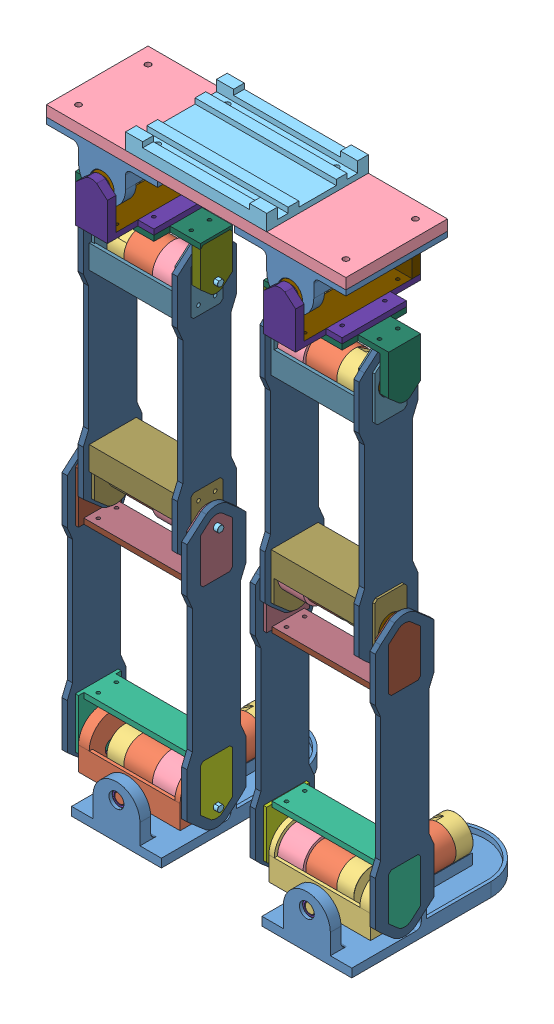
SolidWorks assembly Biped, configuration Default. Lengths in mm.
Overall size (293 593.93 211.17).
118 component instances, 23 part files, 10 mates.
Components (placement in the parent):
- Leg Left-1: Leg Left [Default] at (-89 -541.9264 -37) size (121 569.75 211.17) (flexible)
  - Foot-1: Foot [Default] at origin size (89.58 49 186.67)
  - Motor-1: Motor [Default] at (14.2667 22.6871 -73.752) x (-1 0 0) z (0 0 1) size (45.64 45.64 90) (flexible)
    - Motor Proper-1: Motor Proper [Default] at (14.2667 22.6871 35.252) x (0.971375 -0.237549 0) z (0 0 1) size (33 33 29)
    - Motor Encoder-1: Motor Encoder [Default] at (14.2667 22.6871 20.752) x (0.839139 0.543917 0) z (0 0 1) size (33 33 16)
    - Motor Gearbox-1: Motor Gearbox [Default] at (14.2667 22.6871 49.752) size (38 38 30)
    - Motor Shaft-1: Motor Shaft [Default] at (14.2667 15.6871 60.752) size (6 6 34)
  - Motor-2: Motor [Default] at (-31.252 -0.6871 50.2667) x (0 0 -1) z (1 0 0) size (45.64 45.64 90) (flexible)
    - Motor Proper-1: Motor Proper [Default] at (14.2667 22.6871 35.252) x (0.971375 -0.237549 0) z (0 0 1) size (33 33 29)
    - Motor Encoder-1: Motor Encoder [Default] at (14.2667 22.6871 20.752) x (0.839139 0.543917 0) z (0 0 1) size (33 33 16)
    - Motor Gearbox-1: Motor Gearbox [Default] at (14.2667 22.6871 49.752) size (38 38 30)
    - Motor Shaft-1: Motor Shaft [Default] at (14.2667 15.6871 60.752) x (-1 0 0) z (0 0 1) size (6 6 34)
  - Ankle Bearing-1: Ankle Bearing [Default] at (-57.5 22 36) x (0 0 -1) z (1 0 0) size (40 60 109)
  - Ankle DShaft-1: Ankle DShaft [Default] at (59.5 22 36) x (0 0 1) z (-1 0 0) size (40 57.5 109)
  - Bearing-1: Bearing [Default] at (-5.4134 7 64) size (30.72 30.72 6)
    - Bearing Inner-1: Bearing Inner [Default] at (5.4134 0 0) x (0.99329 0.115652 0) z (0 0 1) size (13.2 13.2 6)
    - Bearing Outer-1: Bearing Outer [Default] at (5.4134 0 0) x (0.586238 0.810139 0) z (0 0 1) size (22 22 6)
  - Bearing-2: Bearing [Default] at (-43.5 14.965 30.5867) x (0 0.00646 0.999979) z (-1 0 0) size (30.72 30.72 6)
    - Bearing Inner-1: Bearing Inner [Default] at (5.4134 0 0) x (0.99329 0.115652 0) z (0 0 1) size (13.2 13.2 6)
    - Bearing Outer-1: Bearing Outer [Default] at (5.4134 0 0) x (0.586238 0.810139 0) z (0 0 1) size (22 22 6)
  - Thigh and Shin-1: Thigh and Shin [Default] at (59.5 23.6603 36) x (0 0 1) z (-1 0 0) size (55 261.21 5)
  - Thigh and Shin-2: Thigh and Shin [Default] at (-52.5 23.6603 36) x (0 0 1) z (-1 0 0) size (55 261.21 5)
  - Knee Bearing-1: Knee Bearing [Default] at (-57.5 234.2132 36) x (0 0 1) z (1 0 0) size (40 60 109)
  - Bearing-3: Bearing [Default] at (-40.5 241.2132 30.5866) x (0 0 1) z (-1 0 0) size (30.72 30.72 6)
    - Bearing Inner-1: Bearing Inner [Default] at (5.4134 0 0) x (0.99329 0.115652 0) z (0 0 1) size (13.2 13.2 6)
    - Bearing Outer-1: Bearing Outer [Default] at (5.4134 0 0) x (0.586238 0.810139 0) z (0 0 1) size (22 22 6)
  - Knee-1: Knee [Default] at (50.5 248.2132 36) x (0 0 -1) z (-1 0 0) size (44 57.5 95)
  - Knee DShaft-1: Knee DShaft [Default] at (59.5 234.2132 36) x (0 0 -1) z (-1 0 0) size (40 57.5 109)
  - Motor-3: Motor [Default] at (-31.252 225.5261 50.2667) x (0 0 -1) z (1 0 0) size (45.64 45.64 90) (flexible)
    - Motor Proper-1: Motor Proper [Default] at (14.2667 22.6871 35.252) x (0.971375 -0.237549 0) z (0 0 1) size (33 33 29)
    - Motor Encoder-1: Motor Encoder [Default] at (14.2667 22.6871 20.752) x (0.839139 0.543917 0) z (0 0 1) size (33 33 16)
    - Motor Gearbox-1: Motor Gearbox [Default] at (14.2667 22.6871 49.752) size (38 38 30)
    - Motor Shaft-1: Motor Shaft [Default] at (14.2667 15.6871 60.752) size (6 6 34)
  - Thigh and Shin-3: Thigh and Shin [Default] at (50.5 236.3735 36) x (0 0 1) z (-1 0 0) size (55 261.21 5)
  - Thigh and Shin-4: Thigh and Shin [Default] at (-37.5 236.3735 36) x (0 0 1) z (-1 0 0) size (55 261.21 5)
  - Hip A-1: Hip A [Default] at (50.5 433.4264 36) x (0 0 1) z (-1 0 0) size (44 57.5 95)
  - Hip Bearing A-1: Hip Bearing A [Default] at (-57.5 447.4264 36) x (0 0 -1) z (1 0 0) size (60 47.81 117)
  - Hip DShaft A-1: Hip DShaft A [Default] at (59.5 447.4264 36) x (0 0 1) z (-1 0 0) size (30 45 109)
  - Bearing-4: Bearing [Default] at (-40.5 440.4264 30.5866) x (0 0 1) z (-1 0 0) size (30.72 30.72 6)
    - Bearing Inner-1: Bearing Inner [Default] at (5.4134 0 0) x (0.99329 0.115652 0) z (0 0 1) size (13.2 13.2 6)
    - Bearing Outer-1: Bearing Outer [Default] at (5.4134 0 0) x (0.586238 0.810139 0) z (0 0 1) size (22 22 6)
  - Motor-4: Motor [Default] at (-31.252 456.1135 21.7333) x (0 0 1) z (1 0 0) size (45.64 45.64 90) (flexible)
    - Motor Proper-1: Motor Proper [Default] at (14.2667 22.6871 35.252) x (0.971375 -0.237549 0) z (0 0 1) size (33 33 29)
    - Motor Encoder-1: Motor Encoder [Default] at (14.2667 22.6871 20.752) x (0.839139 0.543917 0) z (0 0 1) size (33 33 16)
    - Motor Gearbox-1: Motor Gearbox [Default] at (14.2667 22.6871 49.752) size (38 38 30)
    - Motor Shaft-1: Motor Shaft [Default] at (14.2667 15.6871 60.752) size (6 6 34)
  - Bearing-5: Bearing [Default] at (-4.4134 512.9264 80.5) size (30.72 30.72 6)
    - Bearing Inner-1: Bearing Inner [Default] at (5.4134 0 0) x (0.99329 0.115652 0) z (0 0 1) size (13.2 13.2 6)
    - Bearing Outer-1: Bearing Outer [Default] at (5.4134 0 0) x (0.586238 0.810139 0) z (0 0 1) size (22 22 6)
  - Hip Bearing B-1: Hip Bearing B [Default] at (1 505.9264 94.5) x (1 0 0) z (0 0 -1) size (60 45.31 117)
  - Hip DShaft B-1: Hip DShaft B [Default] at (1 505.9264 -22.5) x (-1 0 0) z (0 0 1) size (30 42.5 109)
  - Motor-5: Motor [Default] at (15.2667 497.2393 68.252) x (-1 0 0) z (0 0 -1) size (45.64 45.64 90) (flexible)
    - Motor Proper-1: Motor Proper [Default] at (14.2667 22.6871 35.252) x (0.971375 -0.237549 0) z (0 0 1) size (33 33 29)
    - Motor Encoder-1: Motor Encoder [Default] at (14.2667 22.6871 20.752) x (0.839139 0.543917 0) z (0 0 1) size (33 33 16)
    - Motor Gearbox-1: Motor Gearbox [Default] at (14.2667 22.6871 49.752) size (38 38 30)
    - Motor Shaft-1: Motor Shaft [Default] at (14.2667 15.6871 60.752) size (6 6 34)
  - Hip B-1: Hip B [Default] at (1 519.9264 -10.5) x (-1 0 0) z (0 0 1) size (104 44 95)
  - Ankle Left-1: Ankle Left [Default] at (47.5 22 36) x (0 0 -1) z (1 0 0) size (54 47.05 95)
- Leg Right-1: Leg Right [Default] at (89 -541.9264 -37) size (121 569.75 211.17) (flexible)
  - Foot-1: Foot [Default] at origin size (89.58 49 186.67)
  - Motor-1: Motor [Default] at (14.2667 22.6871 -73.752) x (-1 0 0) z (0 0 1) size (45.64 45.64 90) (flexible)
    - Motor Proper-1: Motor Proper [Default] at (14.2667 22.6871 35.252) x (0.971375 -0.237549 0) z (0 0 1) size (33 33 29)
    - Motor Encoder-1: Motor Encoder [Default] at (14.2667 22.6871 20.752) x (0.839139 0.543917 0) z (0 0 1) size (33 33 16)
    - Motor Gearbox-1: Motor Gearbox [Default] at (14.2667 22.6871 49.752) size (38 38 30)
    - Motor Shaft-1: Motor Shaft [Default] at (14.2667 15.6871 60.752) size (6 6 34)
  - Ankle Right-1: Ankle Right [Default] at (-47.5 22 36) x (0 0 -1) z (1 0 0) size (54 47.05 95)
  - Motor-2: Motor [Default] at (31.252 -0.6871 21.7333) x (0 0 1) z (-1 0 0) size (45.64 45.64 90) (flexible)
    - Motor Proper-1: Motor Proper [Default] at (14.2667 22.6871 35.252) x (0.971375 -0.237549 0) z (0 0 1) size (33 33 29)
    - Motor Encoder-1: Motor Encoder [Default] at (14.2667 22.6871 20.752) x (0.839139 0.543917 0) z (0 0 1) size (33 33 16)
    - Motor Gearbox-1: Motor Gearbox [Default] at (14.2667 22.6871 49.752) size (38 38 30)
    - Motor Shaft-1: Motor Shaft [Default] at (14.2667 15.6871 60.752) x (-1 0 0) z (0 0 1) size (6 6 34)
  - Ankle Bearing-1: Ankle Bearing [Default] at (57.5 22 36) x (0 0 1) z (-1 0 0) size (40 60 109)
  - Ankle DShaft-1: Ankle DShaft [Default] at (-59.5 22 36) x (0 0 -1) z (1 0 0) size (40 57.5 109)
  - Bearing-1: Bearing [Default] at (-5.4134 7 64) size (30.72 30.72 6)
    - Bearing Inner-1: Bearing Inner [Default] at (5.4134 0 0) x (0.99329 0.115652 0) z (0 0 1) size (13.2 13.2 6)
    - Bearing Outer-1: Bearing Outer [Default] at (5.4134 0 0) x (0.586238 0.810139 0) z (0 0 1) size (22 22 6)
  - Bearing-2: Bearing [Default] at (43.5 14.9269 41.4129) x (0 0.013511 -0.999909) z (1 0 0) size (30.72 30.72 6)
    - Bearing Inner-1: Bearing Inner [Default] at (5.4134 0 0) x (0.99329 0.115652 0) z (0 0 1) size (13.2 13.2 6)
    - Bearing Outer-1: Bearing Outer [Default] at (5.4134 0 0) x (0.586238 0.810139 0) z (0 0 1) size (22 22 6)
  - Thigh and Shin-1: Thigh and Shin [Default] at (-59.5 23.6603 36) x (0 0 -1) z (1 0 0) size (55 261.21 5)
  - Thigh and Shin-2: Thigh and Shin [Default] at (52.5 23.6603 36) x (0 0 -1) z (1 0 0) size (55 261.21 5)
  - Knee Bearing-1: Knee Bearing [Default] at (57.5 234.2132 36) x (0 0 -1) z (-1 0 0) size (40 60 109)
  - Bearing-3: Bearing [Default] at (40.5 241.2132 41.4134) x (0 0 -1) z (1 0 0) size (30.72 30.72 6)
    - Bearing Inner-1: Bearing Inner [Default] at (5.4134 0 0) x (0.99329 0.115652 0) z (0 0 1) size (13.2 13.2 6)
    - Bearing Outer-1: Bearing Outer [Default] at (5.4134 0 0) x (0.586238 0.810139 0) z (0 0 1) size (22 22 6)
  - Knee-1: Knee [Default] at (-50.5 248.2132 36) x (0 0 1) z (1 0 0) size (44 57.5 95)
  - Knee DShaft-1: Knee DShaft [Default] at (-59.5 234.2132 36) x (0 0 1) z (1 0 0) size (40 57.5 109)
  - Motor-3: Motor [Default] at (31.252 225.5261 21.7333) x (0 0 1) z (-1 0 0) size (45.64 45.64 90) (flexible)
    - Motor Proper-1: Motor Proper [Default] at (14.2667 22.6871 35.252) x (0.971375 -0.237549 0) z (0 0 1) size (33 33 29)
    - Motor Encoder-1: Motor Encoder [Default] at (14.2667 22.6871 20.752) x (0.839139 0.543917 0) z (0 0 1) size (33 33 16)
    - Motor Gearbox-1: Motor Gearbox [Default] at (14.2667 22.6871 49.752) size (38 38 30)
    - Motor Shaft-1: Motor Shaft [Default] at (14.2667 15.6871 60.752) size (6 6 34)
  - Thigh and Shin-3: Thigh and Shin [Default] at (-50.5 236.3735 36) x (0 0 -1) z (1 0 0) size (55 261.21 5)
  - Thigh and Shin-4: Thigh and Shin [Default] at (37.5 236.3735 36) x (0 0 -1) z (1 0 0) size (55 261.21 5)
  - Hip A-1: Hip A [Default] at (-50.5 433.4264 36) x (0 0 -1) z (1 0 0) size (44 57.5 95)
  - Hip Bearing A-1: Hip Bearing A [Default] at (57.5 447.4264 36) x (0 0 1) z (-1 0 0) size (60 47.81 117)
  - Hip DShaft A-1: Hip DShaft A [Default] at (-59.5 447.4264 36) x (0 0 -1) z (1 0 0) size (30 45 109)
  - Bearing-4: Bearing [Default] at (40.5 440.4264 41.4134) x (0 0 -1) z (1 0 0) size (30.72 30.72 6)
    - Bearing Inner-1: Bearing Inner [Default] at (5.4134 0 0) x (0.99329 0.115652 0) z (0 0 1) size (13.2 13.2 6)
    - Bearing Outer-1: Bearing Outer [Default] at (5.4134 0 0) x (0.586238 0.810139 0) z (0 0 1) size (22 22 6)
  - Motor-4: Motor [Default] at (31.252 456.1135 50.2667) x (0 0 -1) z (-1 0 0) size (45.64 45.64 90) (flexible)
    - Motor Proper-1: Motor Proper [Default] at (14.2667 22.6871 35.252) x (0.971375 -0.237549 0) z (0 0 1) size (33 33 29)
    - Motor Encoder-1: Motor Encoder [Default] at (14.2667 22.6871 20.752) x (0.839139 0.543917 0) z (0 0 1) size (33 33 16)
    - Motor Gearbox-1: Motor Gearbox [Default] at (14.2667 22.6871 49.752) size (38 38 30)
    - Motor Shaft-1: Motor Shaft [Default] at (14.2667 15.6871 60.752) size (6 6 34)
  - Bearing-5: Bearing [Default] at (-6.0005 510.8528 80.5) x (0.923728 0.383049 0) z (0 0 -1) size (30.72 30.72 6)
    - Bearing Inner-1: Bearing Inner [Default] at (5.4134 0 0) x (0.99329 0.115652 0) z (0 0 1) size (13.2 13.2 6)
    - Bearing Outer-1: Bearing Outer [Default] at (5.4134 0 0) x (0.586238 0.810139 0) z (0 0 1) size (22 22 6)
  - Hip Bearing B-1: Hip Bearing B [Default] at (-1 505.9264 94.5) x (1 0 0) z (0 0 -1) size (60 45.31 117)
  - Hip DShaft B-1: Hip DShaft B [Default] at (-1 505.9264 -22.5) x (-1 0 0) z (0 0 1) size (30 42.5 109)
  - Motor-5: Motor [Default] at (13.2667 497.2393 68.252) x (-1 0 0) z (0 0 -1) size (45.64 45.64 90) (flexible)
    - Motor Proper-1: Motor Proper [Default] at (14.2667 22.6871 35.252) x (0.971375 -0.237549 0) z (0 0 1) size (33 33 29)
    - Motor Encoder-1: Motor Encoder [Default] at (14.2667 22.6871 20.752) x (0.839139 0.543917 0) z (0 0 1) size (33 33 16)
    - Motor Gearbox-1: Motor Gearbox [Default] at (14.2667 22.6871 49.752) size (38 38 30)
    - Motor Shaft-1: Motor Shaft [Default] at (14.2667 15.6871 60.752) size (6 6 34)
  - Hip B-1: Hip B [Default] at (-1 519.9264 -10.5) x (-1 0 0) z (0 0 1) size (104 44 95)
- Torso Base-1: Torso Base [Default] at origin size (280 10 95)
- Torso Base Reinforcement-1: Torso Base Reinforcement [Default] at (0 10 0) size (132 15 95)
Mates (geometry in assembly coordinates):
- Coincident1: coordinate: point of Torso Base-1; point of assembly
- Coincident2: coincident anti-aligned: plane of Leg Right-1/Hip B-1 through (66 0 -42.5) normal (0 1 0); plane of Torso Base-1 through (0 0 0) normal (0 -1 0)
- Coincident3: coincident anti-aligned: plane of Leg Left-1/Hip B-1 through (-110 0 -42.5) normal (0 1 0); plane of Torso Base-1 through (0 0 0) normal (0 -1 0)
- Concentric1: concentric aligned: cylinder of Leg Left-1/Hip B-1 through (-125 0 -32.5) axis (0 1 0) radius 2.65; cylinder of Torso Base-1 through (-125 10 -32.5) axis (0 1 0) radius 2.65
- Concentric2: concentric aligned: cylinder of Leg Left-1/Hip B-1 through (-51 0 32.5) axis (0 1 0) radius 2.65; cylinder of Torso Base-1 through (-51 10 32.5) axis (0 1 0) radius 2.65
- Concentric3: concentric aligned: cylinder of Leg Right-1/Hip B-1 through (51 0 -32.5) axis (0 1 0) radius 2.65; cylinder of Torso Base-1 through (51 10 -32.5) axis (0 1 0) radius 2.65
- Concentric4: concentric aligned: cylinder of Leg Right-1/Hip B-1 through (125 0 32.5) axis (0 1 0) radius 2.65; cylinder of Torso Base-1 through (125 10 32.5) axis (0 1 0) radius 2.65
- Coincident4: coincident anti-aligned: plane of Torso Base-1 through (0 10 0) normal (0 1 0); plane of Torso Base Reinforcement-1 through (0 10 0) normal (0 -1 0)
- Concentric5: concentric aligned: cylinder of Torso Base-1 through (-51 10 -32.5) axis (0 1 0) radius 2.65; cylinder of Torso Base Reinforcement-1 through (-51 15 -32.5) axis (0 1 0) radius 2.65
- Concentric6: concentric aligned: cylinder of Torso Base-1 through (51 10 32.5) axis (0 1 0) radius 2.65; cylinder of Torso Base Reinforcement-1 through (51 15 32.5) axis (0 1 0) radius 2.65
